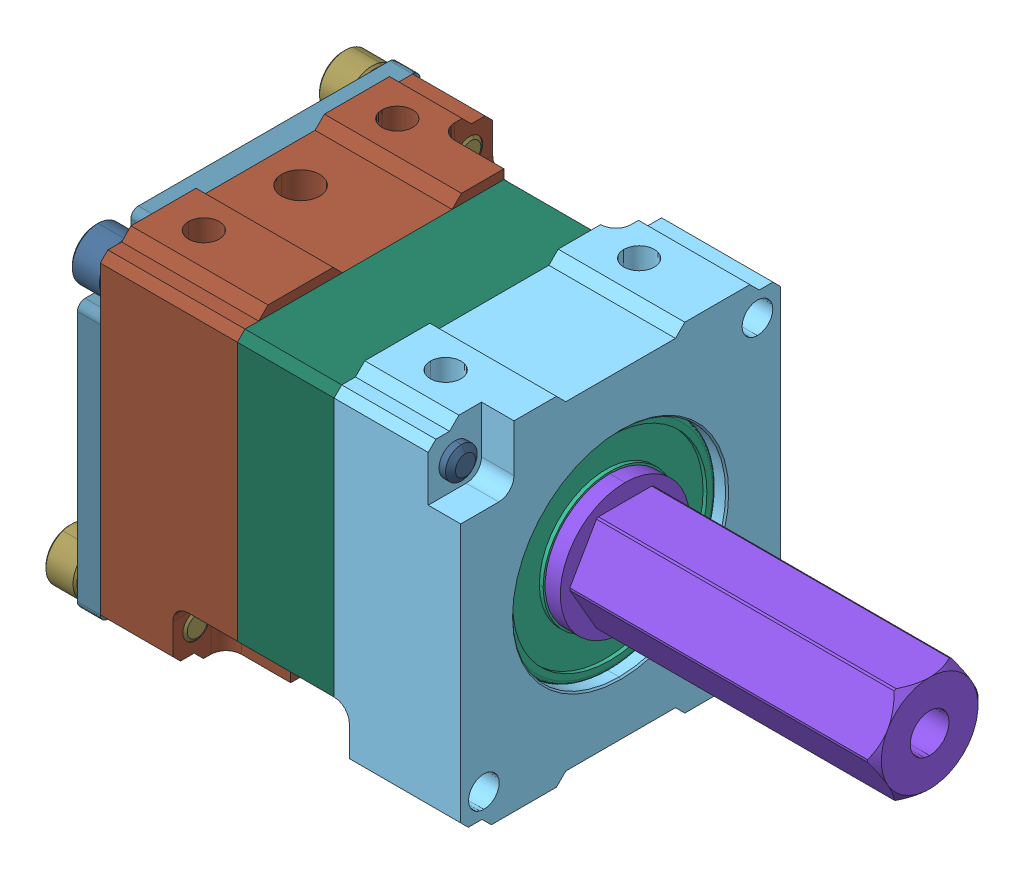
SolidWorks assembly gearbox for rev neo 550, configuration Default. Lengths in mm.
Overall size (97.9 49.04 49.3).
29 component instances, 18 part files, 0 mates.
Components (placement in the parent):
- VersaPlanetary v2 Single Stage 10_1 with BAG .step-1: VersaPlanetary v2 Single Stage 10_1 with BAG .step [Default] at origin size (97.9 49.04 49.3)
  - 217-2820 Rev1_Public.step-1: 217-2820 Rev1_Public.step [Default] at (-4.6546 22.225 0) x (0 -0.456494 0.889726) z (-1 0 0) size (39.22 38.88 17.4)
    - 217-2625-100.step-1: 217-2625-100.step [Default] at origin size (39.22 38.88 12.7)
      - 217-2625-008 Rev1.step-1: 217-2625-008 Rev1.step [Default] at origin size (34.7 34.7 4.7)
      - 217-2625-010 Rev1.step-1: 217-2625-010 Rev1.step [Default] at (0 10.193 3.65) x (0.999813 0.019336 0) z (0 0 1) size (4 4 12)
      - 217-2625-010 Rev1.step-2: 217-2625-010 Rev1.step [Default] at (8.691 -5.3258 3.65) size (4 4 12)
      - 217-2625-010 Rev1.step-3: 217-2625-010 Rev1.step [Default] at (-8.691 -5.3258 3.65) size (4 4 12)
      - 217-2625-005 Rev1_Planet_Revolving_Follower01.step-1: 217-2625-005 Rev1_Planet_Revolving_Follower01.step [Default] at (8.691 -5.3258 6.35) x (0.932816 0.360354 0) z (0 0 1) size (16.89 16.89 8)
      - 217-2625-005 Rev1_Planet_Revolving_Follower01.step-2: 217-2625-005 Rev1_Planet_Revolving_Follower01.step [Default] at (-8.691 -5.3258 6.35) x (-0.932788 -0.360426 0) z (0 0 1) size (16.89 16.89 8)
      - 217-2625-005 Rev1_Planet_Revolving_Follower01.step-3: 217-2625-005 Rev1_Planet_Revolving_Follower01.step [Default] at (0 10.193 6.35) x (0.893583 0.448898 0) z (0 0 1) size (16.89 16.89 8)
    - 217-2625-007 Rev1_Public.step-1: 217-2625-007 Rev1_Public.step [Default] at (0 0 6.7) x (0.992772 0.120019 0) z (0 0 1) size (15.27 15.27 12.7)
  - 217-2625-026 Rev1.step-1: 217-2625-026 Rev1.step [Default] at (-6.5 22.225 0) x (0 -1 0) z (-1 0 0) size (44.45 42 18.12)
  - 217-2742-001 Rev4.step-1: 217-2742-001 Rev4.step [Default] at (0.2002 22.225 0) x (1 0 0) z (0 -0.092627 0.995701) size (7 28 28)
  - 217-2742-001 Rev4.step-2: 217-2742-001 Rev4.step [Default] at (8.2002 22.225 0) size (7 28 28)
  - 217-2625-017 Rev1_9714K61.step-1: 217-2625-017 Rev1_9714K61.step [Default] at (7.42 22.3002 -0.342) x (0 0.56703 0.823697) z (0 -0.823697 0.56703) size (28.51 4.98 27.43)
  - 217-2625-003 Rev1.step-1: 217-2625-003 Rev1.step [Default] at (7.4478 22.225 0) x (0 -1 0) z (1 0 0) size (17 17 64.11)
  - 217-2625-018 Rev1_98541A410.step-1: 217-2625-018 Rev1_98541A410.step [Default] at (-0.7046 22.225 0) x (1 0 0) z (0 -0.017452 0.999848) size (1 19.6 17.4)
  - 832-1750-Ring-Gear-Screw_SSA0832-0500ZC.step-1: 832-1750-Ring-Gear-Screw_SSA0832-0500ZC.step [Default] at (-30.7 4.725 -17.5) x (0 0.997447 0.071411) z (0 -0.071411 0.997447) size (6.73 48.51 6.73)
  - 832-1750-Ring-Gear-Screw_SSA0832-0500ZC.step-2: 832-1750-Ring-Gear-Screw_SSA0832-0500ZC.step [Default] at (-30.7 39.725 17.5) x (0 0.005929 0.999982) z (0 -0.999982 0.005929) size (6.73 48.51 6.73)
  - 217-2625-025 Rev1.step-1: 217-2625-025 Rev1.step [Default] at (-23.2 22.225 0) x (0 -1 0) z (-1 0 0) size (44.45 42 18)
  - 217-4649-002 Rev1_SSA0832-0500ZC.step-1: 217-4649-002 Rev1_SSA0832-0500ZC.step [Default] at (-33.7 4.2645 17.9605) x (0 0.33842 -0.940995) z (0 0.940995 0.33842) size (6.73 16.76 6.73)
  - 217-4649-002 Rev1_SSA0832-0500ZC.step-2: 217-4649-002 Rev1_SSA0832-0500ZC.step [Default] at (-33.7 40.1855 -17.9605) x (0 -0.308932 -0.951084) z (0 0.951084 -0.308932) size (6.73 16.76 6.73)
  - 217-4649-006 Rev1_SSA0004-008BA.step-1: 217-4649-006 Rev1_SSA0004-008BA.step [Default] at (-30.7 22.225 12.5) x (0 0.5 -0.866025) z (0 -0.866025 -0.5) size (7 14 7)
  - 217-4649-006 Rev1_SSA0004-008BA.step-2: 217-4649-006 Rev1_SSA0004-008BA.step [Default] at (-30.7 22.225 -12.5) x (0 -0.5 0.866025) z (0 0.866025 0.5) size (7 14 7)
  - 217-2822-003 Rev4.step-1: 217-2822-003 Rev4.step [Default] at (-32.2 22.225 0) x (0 -1 0) z (-1 0 0) size (42 42 4.8)
  - 217-2816-001 Rev1.step-1: 217-2816-001 Rev1.step [Default] at (-6.35 22.225 0) x (0 -1 0) z (1 0 0) size (42 42 14.51)
  - 217-4649-001 Rev1.step-1: 217-4649-001 Rev1.step [Default] at (-20.046 22.225 0) x (0 -1 0) z (1 0 0) size (18 18 13)
  - 217-4649-007 Rev1_94105A824.step-1: 217-4649-007 Rev1_94105A824.step [Default] at (-25.521 22.225 -6.7835) x (-0.996104 -0.088191 0) z (0 0 -1) size (4.83 4.83 4.77)
  - 217-2625-011 Rev1.step-1: 217-2625-011 Rev1.step [Default] at (-24.7818 22.225 0) x (0 0 1) z (0 -1 0) size (8.01 7.5 7.94)
